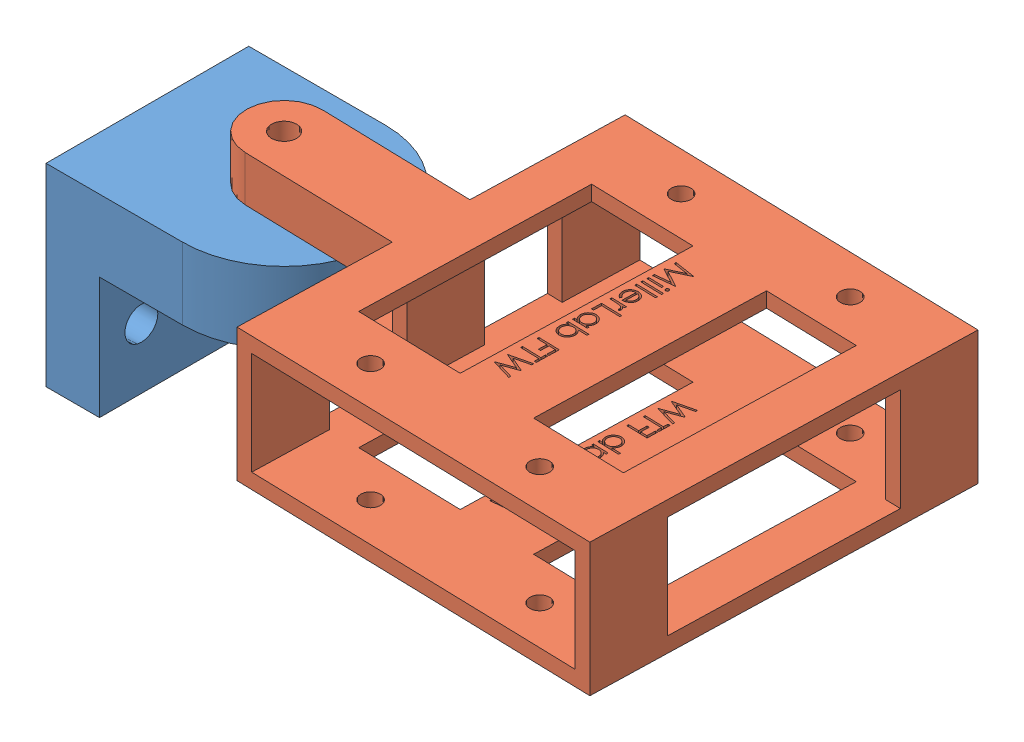
SolidWorks assembly VacuumFasten_001, configuration Default. Lengths in mm.
Overall size (110.15 40.13 66).
2 component instances, 2 part files, 2 mates.
Components (placement in the parent):
- VacuumHinge-1: VacuumHinge [Default] at (-74.2436 51.5862 57.3164) size (39.99 32.51 34.06)
- VacuumHolder-1: VacuumHolder [Default] at (3.7129 64.2862 90.5759) x (0.999629 0 0.027223) z (-0.027223 0 0.999629) size (92.71 22.35 63.5)
Mates (geometry in assembly coordinates):
- Coincident3: coincident anti-aligned: plane of VacuumHinge-1 through (-65.252 67.8422 74.3471) normal (0 1 0); plane of VacuumHolder-1 through (-51.1092 67.8422 50.9687) normal (0 -1 0)
- Concentric1: concentric aligned: circle of VacuumHinge-1; circle of VacuumHolder-1
